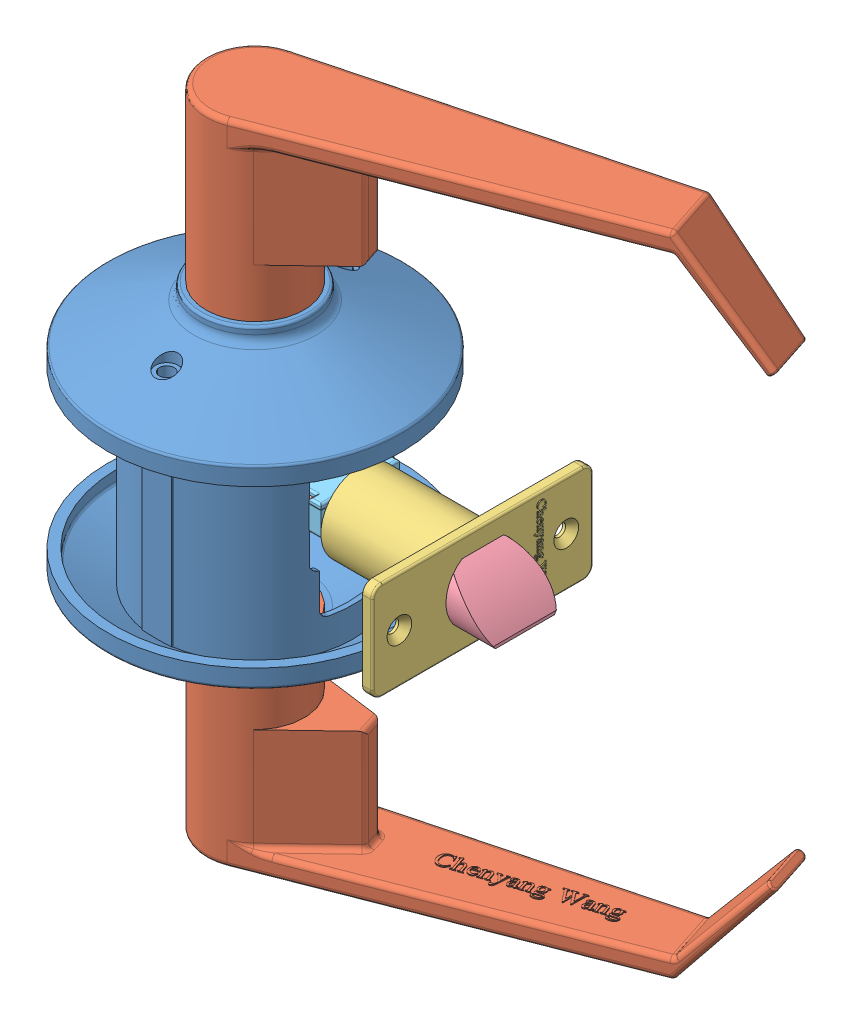
SolidWorks assembly Assem3, configuration Default. Lengths in mm.
Overall size (146.99 167.64 85.09).
10 component instances, 6 part files, 11 mates.
Components (placement in the parent):
- Wang-RoseCover-1: Wang-RoseCover [Rose Cover 2] at origin size (76.2 29.21 76.2)
- Wang-RoseCover-2: Wang-RoseCover [Rose Cover 1] at (0 -40.64 0) x (0 0 1) z (1 0 0) size (76.2 59.69 76.2)
- Wang-Handle-1: Wang-Handle [Handle 2] at (0 -104.14 0) x (0.950966 0 -0.309294) z (0 1 0) size (122.78 27.23 127)
- Wang-Handle-2: Wang-Handle [Handle 1] at (0 63.5 0) x (0.950966 0 -0.309294) z (0 -1 0) size (122.78 27.23 50.8)
- Wang-LatchSubAssembly-1: Wang-LatchSubAssembly [Default] at (56.388 -18.796 0) x (0 -1 0) z (1 0 0) size (25.4 57.15 82) (flexible)
  - Wang-FacePlate-1: Wang-FacePlate [Default] at origin size (25.4 57.15 32)
  - Wang-Latch-1: Wang-Latch [Default] at (0 0 -31.5349) x (0 0 1) z (0 -1 0) size (81.03 15.4 21.46)
  - Wang-LatchPlate-1: Wang-LatchPlate [Default] at (0 0 -29.21) x (0 0 1) z (0 1 0) size (39.37 9.02 20.32)
  - Wang-LatchPlate-2: Wang-LatchPlate [Default] at (-5.334 0 -29.21) x (0 0 1) z (0 -1 0) size (39.37 9.02 20.32)
  - Wang-LockMechanism-1: Wang-LockMechanism [Default] at (-2.794 0 -56.388) x (0 0.309294 0.950966) z (0 -0.950966 0.309294) size (20.32 5.08 18.63)
Mates (geometry in assembly coordinates):
- Concentric3: concentric anti-aligned: cylinder of Wang-RoseCover-1 through (0 19.05 22.86) axis (0 -1 0) radius 1.905; cylinder of Wang-RoseCover-2 through (0 -25.4 22.86) axis (0 1 0) radius 1.905
- Concentric4: concentric anti-aligned: cylinder of Wang-RoseCover-1 through (0 19.05 -22.86) axis (0 -1 0) radius 1.905; cylinder of Wang-RoseCover-2 through (0 -25.4 -22.86) axis (0 1 0) radius 1.905
- Coincident1: coincident anti-aligned: plane of Wang-RoseCover-1 through (0 0 0) normal (0 -1 0); plane of Wang-RoseCover-2 through (0 0 22.86) normal (0 1 0)
- Concentric5: concentric anti-aligned: cylinder of Wang-RoseCover-1 through (0 0 0) axis (0 -1 0) radius 12.7; cylinder of Wang-Handle-2 through (0 12.7 0) axis (0 1 0) radius 12.7
- Concentric6: concentric anti-aligned: cylinder of Wang-RoseCover-2 through (0 -40.64 0) axis (0 1 0) radius 12.7; cylinder of Wang-Handle-1 through (0 -53.34 0) axis (0 -1 0) radius 12.7
- Coincident2: coincident anti-aligned: plane of Wang-Handle-1 through (-0.8296 22.86 3.6085) normal (0.309294 0 0.950966); plane of Wang-Handle-2 through (-0.8296 38.1 3.6085) normal (-0.309294 0 -0.950966)
- Distance2: distance = 12.7 mm anti-aligned: plane of Wang-Handle-2 through (0 31.75 0) normal (0 -1 0); plane of Wang-RoseCover-1 through (12.7 19.05 0) normal (0 1 0)
- Distance3: distance = 12.7 mm anti-aligned: plane of Wang-Handle-1 through (0 -72.39 0) normal (0 1 0); plane of Wang-RoseCover-2 through (0 -59.69 12.7) normal (0 -1 0)
- Coincident3: coincident anti-aligned: plane of Wang-LatchSubAssembly-1 through (56.388 -18.796 0) normal (0 0 -1)
- Coincident5: coincident anti-aligned: plane of Wang-Handle-1 through (-0.8296 22.86 3.6085) normal (0.309294 0 0.950966); plane of Wang-LatchSubAssembly-1/Wang-LockMechanism-1 through (-0.8296 -16.002 3.6085) normal (-0.309294 0 -0.950966)
- Distance5: distance = 6.096 mm anti-aligned: plane of Wang-LatchSubAssembly-1/Wang-FacePlate-1 through (58.928 -6.096 -28.575) normal (0 1 0); plane of Wang-RoseCover-1 through (38.1 0 0) normal (0 -1 0)
